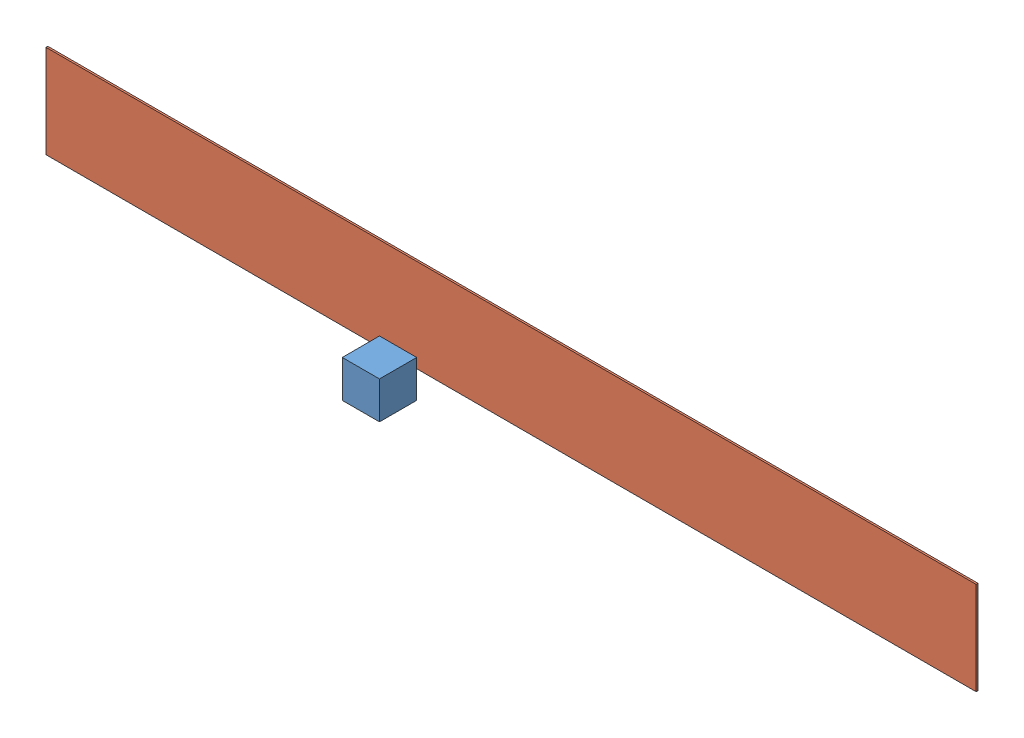
SolidWorks assembly AssemblageCubePlateau, configuration Défaut. Lengths in mm.
Overall size (5000 500 393.14).
2 component instances, 2 part files, 0 mates.
Components (placement in the parent):
- cube-1: cube [Défaut] at (-462.5497 -132.9823 388.1368) size (200 200 200)
- plateau-1: plateau [Défaut] at (-2438.3121 -168.7585 195) size (5000 500 10)
